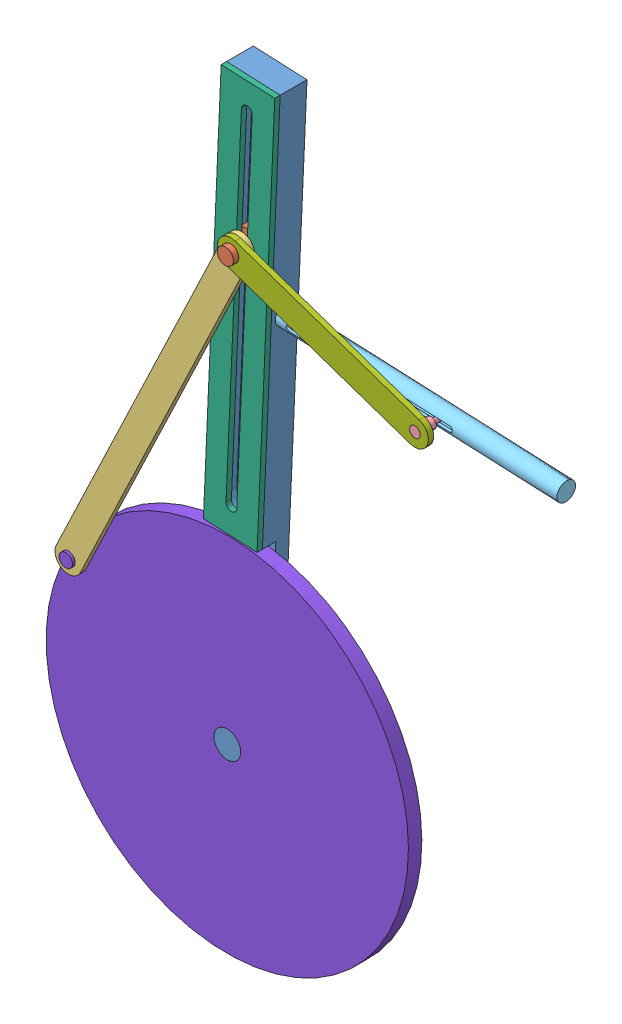
SolidWorks assembly wheel-linkage, configuration Default. Lengths in mm.
Overall size (214.41 313.19 18).
8 component instances, 8 part files, 17 mates.
Components (placement in the parent):
- Base-1: Base [Default] at (67.2248 313.6593 191.8467) x (0.999026 -0.044115 0) z (0 0 1) size (20 230 10)
- Cylinder Connector-1: Cylinder Connector [Default] at (64.8132 259.0463 191.8467) x (1 0 0) z (0 -1 0) size (10 13 10)
- Large Link-1: Large Link [Default] at (33.5687 193.6243 198.8467) x (0.902372 -0.430959 0) z (0 0 1) size (10 155 2)
- Piston-1: Piston [Default] at (133.4386 235.6623 196.8467) x (0.999026 -0.044115 0) z (0 0 1) size (42 5 13.5)
- Piston Cylinder-1: Piston Cylinder [Default] at (113.8675 236.5265 191.8467) x (0.999026 -0.044115 0) z (0 0 1) size (107 7 7)
- Rail Lid-1: Rail Lid [Default] at (63.9162 238.7323 198.8467) x (0.999026 -0.044115 0) z (0.044115 0.999026 0) size (20 7 150)
- Small Link-1: Small Link [Default] at (64.8132 259.0463 200.8467) x (0.322537 0.946557 0) z (0 0 1) size (10 82.5 2)
- Wheel-1: Wheel [Default] at (57.5195 93.8735 194.3467) x (0.528138 0.849159 0) z (0 0 1) size (135 135 10)
Mates (geometry in assembly coordinates):
- Concentric1: concentric aligned: cylinder of Base-1 through (57.5195 93.8735 196.8467) axis (0 0 -1) radius 5; cylinder of Wheel-1 through (57.5195 93.8735 196.8467) axis (0 0 -1) radius 5
- Coincident1: coincident aligned: plane of Base-1 through (57.5195 93.8735 196.8467) normal (0 0 1); plane of Wheel-1 through (57.5195 93.8735 196.8467) normal (0 0 1)
- Coincident2: coincident anti-aligned: plane of Base-1 through (63.9162 238.7323 196.8467) normal (0 0 1); plane of Rail Lid-1 through (63.9162 238.7323 196.8467) normal (0 0 -1)
- Concentric2: concentric aligned: cylinder of Base-1 through (74.0636 309.8539 191.8467) axis (0 0 1) radius 1.5; cylinder of Rail Lid-1 through (74.0636 309.8539 191.8467) axis (0 0 1) radius 1.5
- Coincident3: coincident anti-aligned: plane of Cylinder Connector-1 through (64.8132 259.0463 196.8467) normal (0 0 1); plane of Rail Lid-1 through (63.9162 238.7323 196.8467) normal (0 0 -1)
- Tangent1: tangent anti-aligned: cylinder of Cylinder Connector-1 through (64.8132 259.0463 202.8467) axis (0 0 -1) radius 2; plane of Rail Lid-1 through (64.7856 303.7572 198.8467) normal (0.999026 -0.044115 0)
- Concentric3: concentric aligned: cylinder of Large Link-1 through (2.3242 128.2024 200.8467) axis (0 0 -1) radius 2; cylinder of Wheel-1 through (2.3242 128.2024 200.8467) axis (0 0 -1) radius 2
- Coincident4: coincident anti-aligned: plane of Large Link-1 through (2.3242 128.2024 200.8467) normal (0 0 1); plane of Wheel-1 through (2.3242 128.2024 200.8467) normal (0 0 -1)
- Concentric5: concentric aligned: cylinder of Base-1 through (67.7552 166.9931 191.8467) axis (0 0 1) radius 1.5; cylinder of Rail Lid-1 through (67.7552 166.9931 191.8467) axis (0 0 1) radius 1.5
- Concentric6: concentric aligned: cylinder of Cylinder Connector-1 through (64.8132 259.0463 202.8467) axis (0 0 -1) radius 2; cylinder of Large Link-1 through (64.8132 259.0463 200.8467) axis (0 0 -1) radius 2
- Concentric7: concentric aligned: cylinder of Cylinder Connector-1 through (64.8132 259.0463 202.8467) axis (0 0 -1) radius 2; cylinder of Small Link-1 through (64.8132 259.0463 202.8467) axis (0 0 -1) radius 2
- Coincident5: coincident anti-aligned: plane of Cylinder Connector-1 through (64.8132 259.0463 202.8467) normal (0 0 -1); plane of Small Link-1 through (133.4386 235.6623 202.8467) normal (0 0 1)
- Concentric8: concentric aligned: cylinder of Base-1 through (71.9084 238.3794 191.8467) axis (0.999026 -0.044115 0) radius 1.5; cylinder of Piston Cylinder-1 through (71.9084 238.3794 191.8467) axis (0.999026 -0.044115 0) radius 1.5
- Coincident6: coincident anti-aligned: plane of Base-1 through (70.5978 163.3642 196.8467) normal (0.999026 -0.044115 0); plane of Piston Cylinder-1 through (73.9065 238.2911 191.8467) normal (-0.999026 0.044115 0)
- Concentric9: concentric anti-aligned: cylinder of Piston-1 through (173.3997 233.8977 191.8467) axis (-0.999026 0.044115 0) radius 1; cylinder of Piston Cylinder-1 through (66.8423 238.6031 191.8467) axis (0.999026 -0.044115 0) radius 2.5
- Concentric10: concentric aligned: cylinder of Piston-1 through (133.4386 235.6623 202.8467) axis (0 0 -1) radius 2; cylinder of Small Link-1 through (133.4386 235.6623 202.8467) axis (0 0 -1) radius 2
- Angle1: planar angle = 0.401426 rad aligned: plane of Base-1 through (50.6173 164.2465 196.8467) normal (-0.999026 0.044115 0); plane of Large Link-1 through (-2.1877 130.3572 200.8467) normal (-0.902372 0.430959 0)
